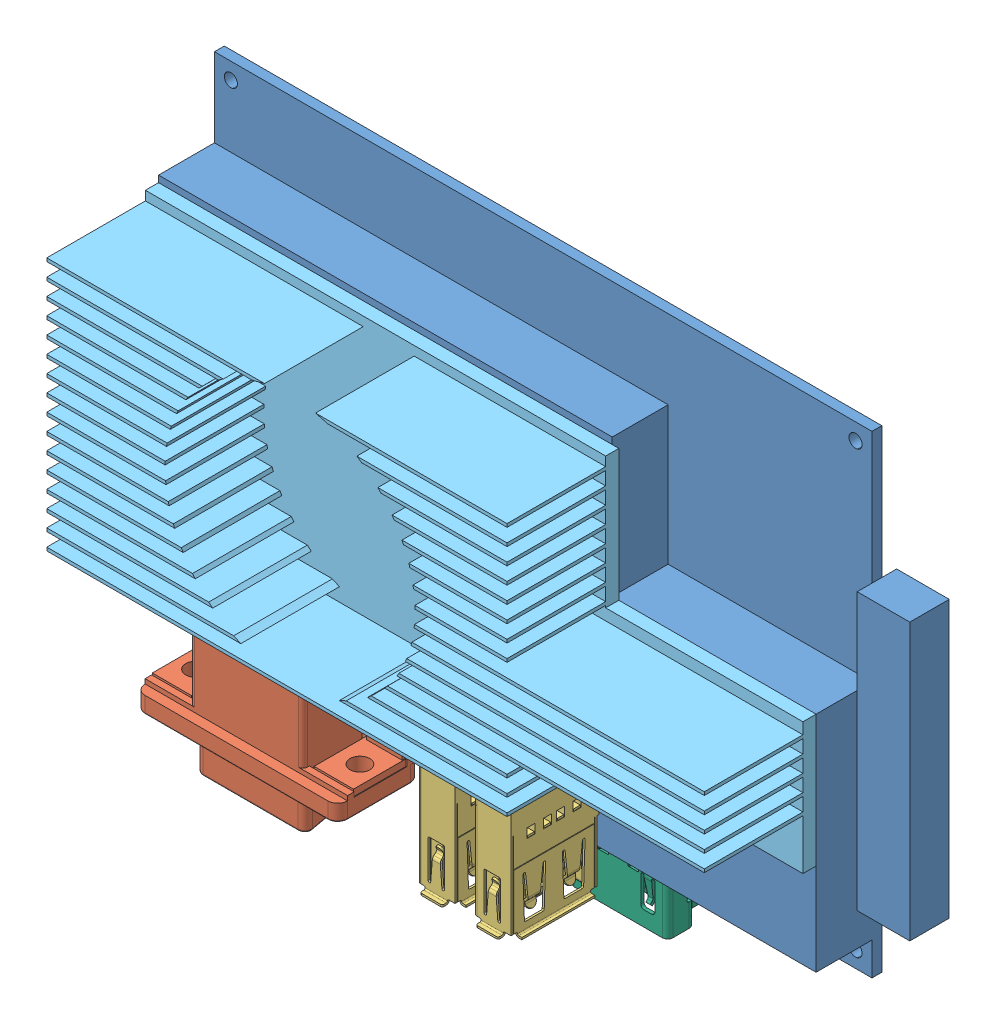
SolidWorks assembly Epia830A, configuration Défaut. Lengths in mm.
Overall size (108 77.9 34.25).
8 component instances, 7 part files, 15 mates.
Components (placement in the parent):
- Epia830A-1: Epia830A [Défaut] at (-69.8392 -40.6536 99.25) size (108 72 12.25)
- HDL 15-SL-B-1: HDL 15-SL-B [По умолчанию] at (-45.9392 -40.6536 115.025) x (-1 0 0) z (0 1 0) size (30.8 16.47 22.2)
- USB-A 111 (vertical on plate)-1: USB-A 111 (vertical on plate) [По умолчанию] at (-10.7453 -27.6536 116.1) x (0 -1 0) z (0 0 -1) size (19.3 7.1 18.4)
- USB-A 111 (vertical on plate)-2: USB-A 111 (vertical on plate) [По умолчанию] at (-2.2453 -27.6536 116.1) x (0 -1 0) z (0 0 -1) size (19.3 7.1 18.4)
- DDR2 SO-DIMM-1: DDR2 SO-DIMM [1.5V] at (-31.0392 21.3464 93.75) x (1 0 0) z (0 1 0) size (67.6 3.5 30)
- Epia830A-Dissipator-1: Epia830A-Dissipator [Défaut] at (-69.8392 -21.6536 109.25) size (100 40 17)
- RJ45.ipt-1: RJ45.ipt [Défaut] at (14.2233 -40.6536 116.108) x (-1 0 0) z (0 -1 0) (suppressed, hidden)
- HDMI_Socket-1: HDMI_Socket [Défaut] at (-2.3392 -45.2235 100.6) x (1 0 0) z (0 -1 0) size (15.14 8.38 12.15)
Mates (geometry in assembly coordinates):
- Distance1: distance = 8 mm anti-aligned: plane of Epia830A-1 through (-69.8392 -40.6536 100.75) normal (0 0 1); plane of HDL 15-SL-B-1 through (-32.0392 -38.1536 108.75) normal (0 0 -1)
- Coïncidente2: coincident aligned: plane of Epia830A-1 through (30.1608 -40.6536 100.75) normal (0 -1 0); plane of HDL 15-SL-B-1 through (-59.8392 -40.6536 110.25) normal (0 -1 0)
- Distance2: distance = 8.5 mm aligned: plane of HDL 15-SL-B-1 through (-61.3392 -38.1536 110.25) normal (-1 0 0); plane of Epia830A-1 through (-69.8392 31.3464 100.75) normal (-1 0 0)
- Distance3: distance = 8 mm anti-aligned: plane of Epia830A-1 through (-69.8392 -40.6536 100.75) normal (0 0 1); plane of USB-A 111 (vertical on plate)-1 through (-10.7453 -27.6536 108.75) normal (0 0 -1)
- Coïncidente6: coincident aligned: plane of Epia830A-1 through (30.1608 -40.6536 100.75) normal (0 -1 0); plane of USB-A 111 (vertical on plate)-1 through (-15.8953 -40.6536 110.55) normal (0 -1 0)
- Distance4: distance = 5 mm anti-aligned: plane of DDR2 SO-DIMM-1 through (-64.8392 -8.6536 94.25) normal (0 0 1); plane of Epia830A-1 through (-69.8392 -40.6536 99.25) normal (0 0 -1)
- Distance5: distance = 10 mm aligned: plane of DDR2 SO-DIMM-1 through (-64.8392 21.3464 93.25) normal (0 1 0); plane of Epia830A-1 through (30.1608 31.3464 100.75) normal (0 1 0)
- Coïncidente9: coincident aligned: plane of Epia830A-1 through (-69.8392 31.3464 100.75) normal (-1 0 0); plane of Epia830A-Dissipator-1 through (-69.8392 -21.6536 111.25) normal (-1 0 0)
- Distance6: distance = 19 mm aligned: plane of Epia830A-Dissipator-1 through (-69.8392 -21.6536 111.25) normal (0 -1 0); plane of Epia830A-1 through (30.1608 -40.6536 100.75) normal (0 -1 0)
- Distance7: distance = 8.5 mm anti-aligned: plane of Epia830A-Dissipator-1 through (-69.8392 -21.6536 109.25) normal (0 0 -1); plane of Epia830A-1 through (-69.8392 -40.6536 100.75) normal (0 0 1)
- Coïncidente13: coincident aligned: plane of Epia830A-1 through (30.1608 -40.6536 100.75) normal (0 -1 0); plane of RJ45.ipt-1 through (22.4783 -40.6536 122.9812) normal (0 -1 0)
- Distance8: distance = 8.5 mm anti-aligned: plane of RJ45.ipt-1 through (22.7424 -19.6682 109.25) normal (0 0 -1); plane of Epia830A-1 through (-69.8392 -40.6536 100.75) normal (0 0 1)
- Distance9: distance = 8 mm aligned: plane of RJ45.ipt-1 through (22.1608 -25.4975 122.9762) normal (1 0 0); plane of Epia830A-1 through (30.1608 31.3464 100.75) normal (1 0 0)
- Coïncidente14: coincident anti-aligned: plane of Epia830A-1 through (-69.8392 -40.6536 100.75) normal (0 0 1); plane of HDMI_Socket-1 through (-1.5892 -33.0735 100.75) normal (0 0 -1)
- Distance10: distance = 5 mm aligned: plane of DDR2 SO-DIMM-1 through (-64.8392 21.3464 93.25) normal (-1 0 0); plane of Epia830A-1 through (-69.8392 31.3464 100.75) normal (-1 0 0)
